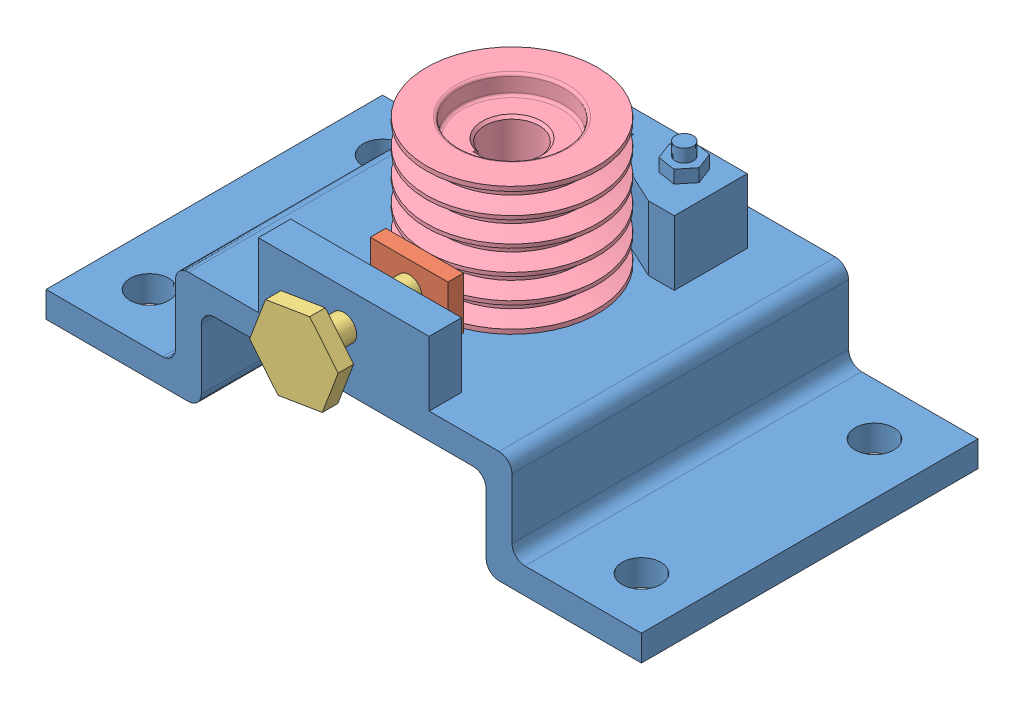
SolidWorks assembly 夹具, configuration 默认. Lengths in mm.
Overall size (460 185.6 298.5).
4 component instances, 4 part files, 6 mates.
Components (placement in the parent):
- 钻床夹具-1: 钻床夹具 [默认] at (8.1296 1.3775 0) size (460 156.6 260)
- 挡板-2: 挡板 [默认] at (8.1296 44.4578 79.4964) x (-1 0 0) z (0 0 -1) size (60 40 12)
- 钻床夹具钉-1: 钻床夹具钉 [默认] at (8.1296 44.4578 168.4964) x (0.647711 -0.761886 0) z (0.761886 0.647711 0) size (69.27 92 60.61)
- 带轮-1: 带轮 [默认] at (-12.7616 40.4253 0) x (0 1 0) z (0 0 1) size (99 132 132)
Mates (geometry in assembly coordinates):
- 同心1: concentric aligned: cylinder of 钻床夹具-1 through (8.1296 44.4578 80) axis (0 0 1) radius 10; cylinder of 钻床夹具钉-1 through (8.1296 44.4578 76.4964) axis (0 0 1) radius 10
- 重合1: coincident anti-aligned: plane of 挡板-2 through (8.1296 44.4578 76.4964) normal (0 0 1); plane of 钻床夹具钉-1 through (8.1296 44.4578 76.4964) normal (0 0 -1)
- 同心3: concentric aligned: cylinder of 挡板-2 through (8.1296 44.4578 76.4964) axis (0 0 1) radius 10; cylinder of 钻床夹具钉-1 through (8.1296 44.4578 76.4964) axis (0 0 1) radius 10
- 平行1: parallel aligned: plane of 钻床夹具-1 through (74.1296 71.3775 105) normal (0 1 0); plane of 挡板-2 through (38.1296 64.4578 67.4964) normal (0 1 0)
- 同心4: concentric anti-aligned: circle of 钻床夹具-1; circle of 带轮-1
- 重合3: coincident anti-aligned: plane of 钻床夹具-1 through (8.1296 21.3775 130) normal (0 1 0); plane of 带轮-1 through (67.8182 21.3775 0) normal (0 -1 0)
